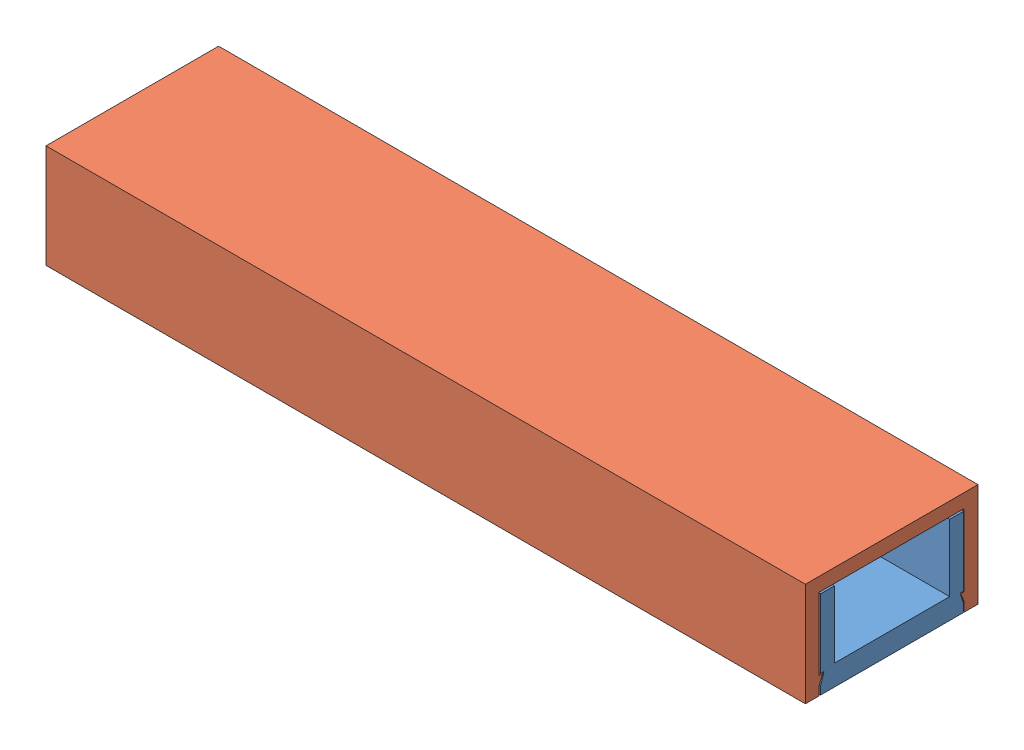
SolidWorks assembly Ensamblaje1, configuration Default. Lengths in mm.
Overall size (110 15 25).
2 component instances, 2 part files, 3 mates.
Components (placement in the parent):
- Embellecedores cables estanterias base vertical-1: Embellecedores cables estanterias base vertical [Default] at (46.8341 43.4373 86.5622) size (110 12.7 20.7)
- Embellecedores cables estanterias tapa vertical-1: Embellecedores cables estanterias tapa vertical [Default] at (46.8341 43.4373 86.6122) size (110 15 25)
Mates (geometry in assembly coordinates):
- Coincidente1: coincident: plane of Embellecedores cables estanterias base vertical-1 through (46.8341 43.4373 86.5622) normal (0 -1 0); plane of Embellecedores cables estanterias tapa vertical-1 through (46.8341 43.4373 86.6122) normal (0 -1 0)
- Coincidente2: coincident: plane of Embellecedores cables estanterias base vertical-1 through (101.8341 46.4373 86.5622) normal (1 0 0); plane of Embellecedores cables estanterias tapa vertical-1 through (101.8341 58.4373 86.6122) normal (1 0 0)
- Distancia1: distance = 0.2 mm anti-aligned: plane of Embellecedores cables estanterias tapa vertical-1 through (221.8341 56.4373 97.1122) normal (0 0 -1); plane of Embellecedores cables estanterias base vertical-1 through (46.8341 46.4373 96.9122) normal (0 0 1)
